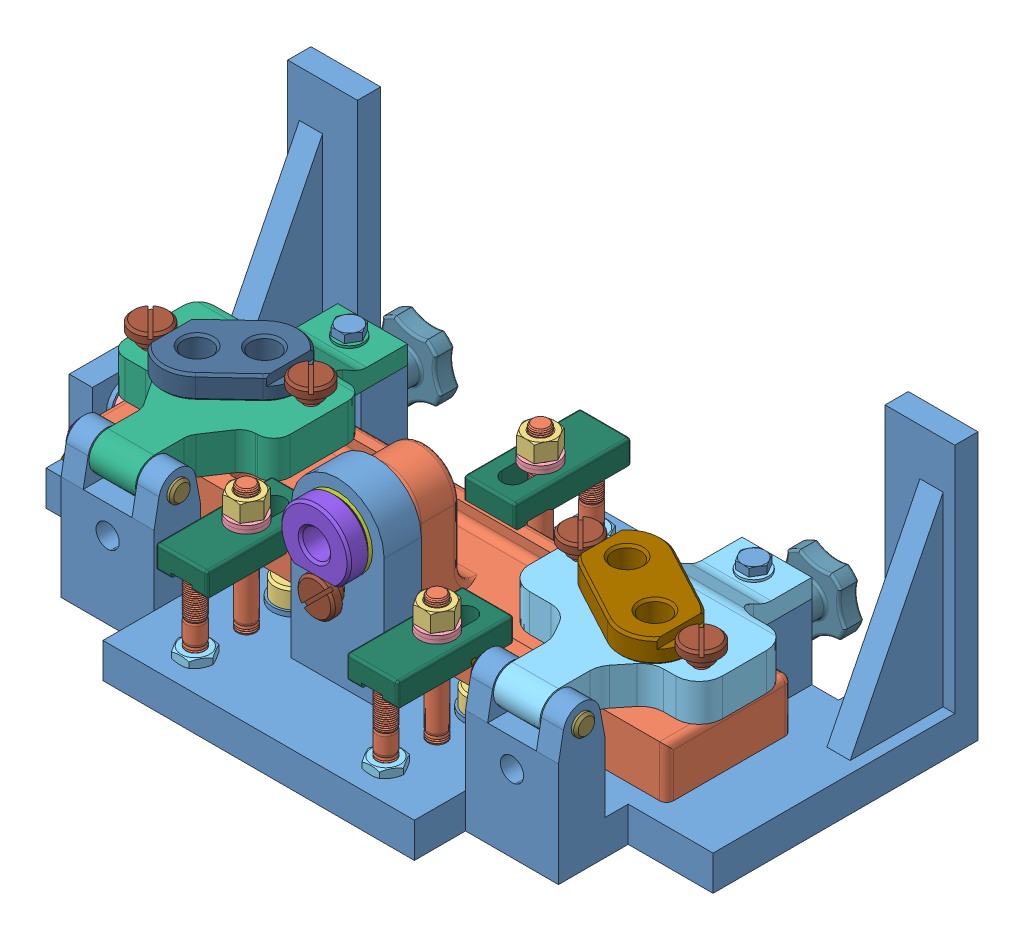
SolidWorks assembly 钻床夹具_4, configuration 默认. Lengths in mm.
Overall size (287 115 166).
59 component instances, 23 part files, 146 mates.
Components (placement in the parent):
- 钻床夹具（新1）-1: 钻床夹具（新1） [默认] at (194.1772 106.0566 199.8684) size (287 115 166)
- 前横架-1: 前横架 [默认] at (70.6772 129.0566 147.8684) x (1 0 0) z (0 1 0) size (247 54 64)
- A型支承钉-1: A型支承钉 [默认] at (194.1772 131.0566 96.8684) size (16 20 16)
- B型支承钉-1: B型支承钉 [默认] at (281.1772 139.0566 147.8684) x (1 0 0) z (0 1 0) size (16 20 16)
- A型支承钉-2: A型支承钉 [默认] at (235.1772 131.0566 143.8684) size (16 20 16)
- A型支承钉-3: A型支承钉 [默认] at (153.1772 131.0566 143.8684) size (16 20 16)
- B型支承钉-2: B型支承钉 [默认] at (107.1772 139.0566 147.8684) x (1 0 0) z (0 1 0) size (16 20 16)
- B型支承钉-3: B型支承钉 [默认] at (70.6772 139.0566 122.8684) x (0 0 1) z (0 1 0) size (16 20 16)
- 钻模板大-1: 钻模板大 [默认] at (292.6772 153.0566 127.8684) size (83 16 112)
- 钻模板小-1: 钻模板小 [默认] at (95.6772 153.0566 127.8684) size (71 16 112)
- 衬套-1: 衬套 [默认] at (194.1772 178.0566 149.8684) x (1 0 0) z (0 -1 0) size (30 16 30)
- 可换钻套-1: 可换钻套 [默认] at (194.1772 178.0566 149.8684) x (0 -1 0) z (-1 0 0) size (30 26 30)
- 特殊钻套1-1: 特殊钻套1 [默认] at (292.6772 153.0566 127.8684) x (1 0 0) z (0 1 0) size (56 44 26)
- 特殊钻套2-1: 特殊钻套2 [默认] at (110.6772 153.0566 113.8684) x (-1 0 0) z (0 1 0) size (45 44 26)
- 钻套螺钉M6×4-2: 钻套螺钉M6×4 [默认] at (194.1772 158.0566 157.8684) x (-0.707107 -0.707107 0) z (-0.707107 0.707107 0) size (16 18 16)
- 钻套螺钉M6×4-1: 钻套螺钉M6×4 [默认] at (130.6772 161.0566 113.8684) x (0.707107 0 0.707107) z (-0.707107 0 0.707107) size (16 18 16)
- 钻套螺钉M6×4-3: 钻套螺钉M6×4 [默认] at (75.6772 161.0566 127.8684) x (-0.707107 0 -0.707107) z (0.707107 0 -0.707107) size (16 18 16)
- 钻套螺钉M6×4-4: 钻套螺钉M6×4 [默认] at (246.6772 161.0566 113.8684) x (0.707107 0 0.707107) z (-0.707107 0 0.707107) size (16 18 16)
- 钻套螺钉M6×4-5: 钻套螺钉M6×4 [默认] at (312.6772 161.0566 127.8684) x (0.707107 0 0.707107) z (-0.707107 0 0.707107) size (16 18 16)
- 铰链轴-1: 铰链轴 [默认] at (256.1772 161.0566 167.8684) x (0 -0.707107 0.707107) z (-1 0 0) size (9 9 47)
- 铰链轴-2: 铰链轴 [默认] at (82.1772 161.0566 167.8684) x (0 0.707107 0.707107) z (-1 0 0) size (9 9 47)
- AM6×50压紧螺钉-1: AM6×50压紧螺钉 [默认] at (281.1772 139.0566 43.8684) x (-0.707107 -0.707107 0) z (0 0 -1) size (6.06 6.06 49.99)
- AM6×50压紧螺钉-2: AM6×50压紧螺钉 [默认] at (107.1772 139.0566 43.8684) x (-0.707107 -0.707107 0) z (0 0 -1) size (6.06 6.06 49.99)
- BM6星形把手-1: BM6星形把手 [默认] at (281.1772 139.0566 41.8684) x (-0.707107 0.707107 0) z (0 0 -1) size (31.86 30.53 18.06)
- BM6星形把手-2: BM6星形把手 [默认] at (107.1772 139.0566 41.8684) x (-0.707107 0.707107 0) z (0 0 -1) size (31.86 30.53 18.06)
- A8×50移动压板-2: A8×50移动压板 [默认] at (224.1772 151.0566 142.1184) x (0 0 1) z (-1 0 0) size (50 10 22)
- A8×50移动压板-3: A8×50移动压板 [默认] at (205.1772 151.0566 100.6184) x (0 0 -1) z (1 0 0) size (50 10 22)
- A8×50移动压板-1: A8×50移动压板 [默认] at (142.1772 151.0566 142.1184) x (0 0 1) z (-1 0 0) size (50 10 22)
- 辅助支撑螺柱_小-1: 辅助支撑螺柱_小 [默认] at (103.1772 101.7128 120.8684) size (8 20 8)
- 辅助支撑螺柱_小-2: 辅助支撑螺柱_小 [默认] at (279.6772 101.7128 120.8684) size (8 20 8)
- plain washers-n series-grade a gb-1: plain washers-n series-grade a gb [GB_FASTENER_WASHER_PWNA 6] at (85.3188 161.0566 167.8684) x (0 0 1) z (-1 0 0) size (12 12 1.6)
- plain washers-n series-grade a gb-2: plain washers-n series-grade a gb [GB_FASTENER_WASHER_PWNA 6] at (259.4007 161.0566 167.8684) x (0 0 1) z (-1 0 0) size (12 12 1.6)
- split pins-1: split pins [GB_CONNECTING_PIECE_PIN_AP 1.6X10] at (84.6772 165.4406 163.4843) x (0 -0.707107 0.707107) z (1 0 0) size (15.7 2.8 1.4)
- split pins-2: split pins [GB_CONNECTING_PIECE_PIN_AP 1.6X10] at (258.6772 165.4406 172.2525) x (0 -0.707107 -0.707107) z (1 0 0) size (15.7 2.8 1.4)
- hex head bolts-full thread grade c gb-7: hex head bolts-full thread grade c gb [GB_FASTENER_BOLT_HHBFTC M6X16-N] at (281.1772 166.0566 73.8686) x (0 -1 0) z (-0.866025 0 0.5) size (20 11.55 10)
- hex head bolts-full thread grade c gb-6: hex head bolts-full thread grade c gb [GB_FASTENER_BOLT_HHBFTC M6X16-N] at (107.1772 166.0566 73.8684) x (0 -1 0) z (0 0 -1) size (20 11.55 10)
- double end studs bm=2d gb-1: double end studs bm=2d gb [GB_FASTENER_BOLT_DESB20 A M8X25-S] at (235.1772 112.0566 186.1184) x (0 1 0) z (0 0 1) size (41 8 8)
- double end studs bm=2d gb-2: double end studs bm=2d gb [GB_FASTENER_BOLT_DESB20 A M8X50-S] at (235.1772 109.0566 164.1184) x (0 1 0) z (0 0 1) size (66 8 8)
- hex nut-fine pitch-style washer-grade ab gb-1: hex nut-fine pitch-style washer-grade ab gb [GB_HEXAGON_TYPE10_1 M8X1-S] at (235.1772 164.8566 164.1184) x (-1 0 0) z (0 -1 0) size (15.01 13 8.1)
- double end studs bm=2d gb-3: double end studs bm=2d gb [GB_FASTENER_BOLT_DESB20 A M8X50-S] at (153.1772 109.0566 164.1184) x (0 1 0) z (0.210743 0 0.977541) size (66 8 8)
- double end studs bm=2d gb-4: double end studs bm=2d gb [GB_FASTENER_BOLT_DESB20 A M8X50-S] at (194.1772 109.0566 78.6184) x (0 1 0) z (-0.024503 0 0.9997) size (66 8 8)
- hex nut-fine pitch-style washer-grade ab gb-2: hex nut-fine pitch-style washer-grade ab gb [GB_HEXAGON_TYPE10_1 M8X1-S] at (153.1772 164.8566 164.1184) x (-1 0 0) z (0 -1 0) size (15.01 13 8.1)
- double end studs bm=2d gb-5: double end studs bm=2d gb [GB_FASTENER_BOLT_DESB20 A M8X25-S] at (153.1772 112.0566 186.1184) x (0 1 0) z (0 0 1) size (41 8 8)
- double end studs bm=2d gb-6: double end studs bm=2d gb [GB_FASTENER_BOLT_DESB20 A M8X25-S] at (194.1772 112.0566 56.6184) x (0 1 0) z (0 0 1) size (41 8 8)
- plain washers-s series-grade a gb-1: plain washers-s series-grade a gb [GB_FASTENER_WASHER_PWSA 8] at (235.1772 162.6566 164.1184) x (-0.768939 0 -0.639322) z (0 1 0) size (15 15 1.6)
- plain washers-s series-grade a gb-2: plain washers-s series-grade a gb [GB_FASTENER_WASHER_PWSA 8] at (235.1772 162.6566 164.1184) x (-0.41646 0 0.909154) z (0 -1 0) size (15 15 1.6)
- plain washers-n series-grade a gb-4: plain washers-n series-grade a gb [GB_FASTENER_WASHER_PWNA 8] at (235.1772 151.0566 164.1184) x (1 0 0) z (0 1 0) size (16 16 1.6)
- hex nut-fine pitch-style washer-grade ab gb-3: hex nut-fine pitch-style washer-grade ab gb [GB_HEXAGON_TYPE10_1 M8X1-S] at (194.1772 164.8566 78.6184) x (-1 0 0) z (0 -1 0) size (15.01 13 8.1)
- plain washers-s series-grade a gb-3: plain washers-s series-grade a gb [GB_FASTENER_WASHER_PWSA 8] at (153.1772 161.0566 164.1184) x (1 0 0) z (0 -1 0) size (15 15 1.6)
- plain washers-s series-grade a gb-4: plain washers-s series-grade a gb [GB_FASTENER_WASHER_PWSA 8] at (153.1772 162.6566 164.1184) x (1 0 0) z (0 -1 0) size (15 15 1.6)
- plain washers-s series-grade a gb-5: plain washers-s series-grade a gb [GB_FASTENER_WASHER_PWSA 8] at (194.1772 164.2566 78.6184) x (1 0 0) z (0 1 0) size (15 15 1.6)
- plain washers-s series-grade a gb-6: plain washers-s series-grade a gb [GB_FASTENER_WASHER_PWSA 8] at (194.1772 162.6566 78.6184) x (1 0 0) z (0 1 0) size (15 15 1.6)
- plain washers-n series-grade a gb-3: plain washers-n series-grade a gb [GB_FASTENER_WASHER_PWNA 8] at (153.1772 151.0566 164.1184) x (1 0 0) z (0 1 0) size (16 16 1.6)
- plain washers-n series-grade a gb-5: plain washers-n series-grade a gb [GB_FASTENER_WASHER_PWNA 8] at (194.1772 151.0566 78.6184) x (1 0 0) z (0 1 0) size (16 16 1.6)
- hex thin nuts-grades ab-chamfered gb-1: hex thin nuts-grades ab-chamfered gb [GB_FASTENER_NUT_STNAB M8-N] at (153.1772 125.0566 186.1184) x (1 0 0) z (0 1 0) size (15.01 13 4)
- hex thin nuts-grades ab-chamfered gb-2: hex thin nuts-grades ab-chamfered gb [GB_FASTENER_NUT_STNAB M8-N] at (235.1772 125.0566 186.1184) x (1 0 0) z (0 1 0) size (15.01 13 4)
- hex thin nuts-grades ab-chamfered gb-3: hex thin nuts-grades ab-chamfered gb [GB_FASTENER_NUT_STNAB M8-N] at (194.1772 125.0566 56.6184) x (1 0 0) z (0 1 0) size (15.01 13 4)
- hex thin nuts-grades ab-chamfered gb-4: hex thin nuts-grades ab-chamfered gb [GB_FASTENER_NUT_STNAB M8-N] at (103.1772 125.0566 120.8684) x (1 0 0) z (0 1 0) size (15.01 13 4)
- hex thin nuts-grades ab-chamfered gb-5: hex thin nuts-grades ab-chamfered gb [GB_FASTENER_NUT_STNAB M8-N] at (279.6772 125.0566 120.8684) x (1 0 0) z (0 1 0) size (15.01 13 4)
Mates (geometry in assembly coordinates):
- 同心1: concentric: cylinder of assembly; cylinder of assembly; cylinder of 钻床夹具（新1）-1 through (235.1772 108.0566 143.8684) axis (0 1 0) radius 5; cylinder of A型支承钉-2 through (235.1772 111.0566 143.8684) axis (0 -1 0) radius 5
- 重合1: coincident: plane of assembly; plane of assembly; plane of 钻床夹具（新1）-1 through (235.1772 123.0566 143.8684) normal (0 1 0); plane of A型支承钉-2 through (243.1772 123.0566 143.8684) normal (0 -1 0)
- 同心2: concentric: cylinder of assembly; cylinder of assembly; cylinder of 钻床夹具（新1）-1 through (153.1772 108.0566 143.8684) axis (0 1 0) radius 5; cylinder of A型支承钉-3 through (153.1772 111.0566 143.8684) axis (0 -1 0) radius 5
- 重合2: coincident: plane of assembly; plane of assembly; plane of 钻床夹具（新1）-1 through (153.1772 123.0566 143.8684) normal (0 1 0); plane of A型支承钉-3 through (161.1772 123.0566 143.8684) normal (0 -1 0)
- 同心3: concentric: cylinder of assembly; cylinder of assembly; cylinder of 钻床夹具（新1）-1 through (194.1772 108.0566 96.8684) axis (0 1 0) radius 5; cylinder of A型支承钉-1 through (194.1772 111.0566 96.8684) axis (0 -1 0) radius 5
- 重合3: coincident: plane of assembly; plane of assembly; plane of 钻床夹具（新1）-1 through (194.1772 123.0566 96.8684) normal (0 1 0); plane of A型支承钉-1 through (202.1772 123.0566 96.8684) normal (0 -1 0)
- 同心4: concentric: cylinder of assembly; cylinder of assembly; cylinder of 钻床夹具（新1）-1 through (107.1772 139.0566 199.8694) axis (0 0 -1) radius 5; cylinder of B型支承钉-2 through (107.1772 139.0566 167.8684) axis (0 0 1) radius 5
- 重合4: coincident: plane of assembly; plane of assembly; plane of 钻床夹具（新1）-1 through (107.1772 139.0566 155.8684) normal (0 0 -1); plane of B型支承钉-2 through (115.1772 139.0566 155.8684) normal (0 0 1)
- 同心5: concentric: cylinder of assembly; cylinder of assembly; cylinder of 钻床夹具（新1）-1 through (281.1772 139.0566 199.8694) axis (0 0 -1) radius 5; cylinder of B型支承钉-1 through (281.1772 139.0566 167.8684) axis (0 0 1) radius 5
- 重合5: coincident: plane of assembly; plane of assembly; plane of 钻床夹具（新1）-1 through (281.1772 139.0566 155.8684) normal (0 0 -1); plane of B型支承钉-1 through (289.1772 139.0566 155.8684) normal (0 0 1)
- 同心6: concentric: cylinder of assembly; cylinder of assembly; cylinder of 钻床夹具（新1）-1 through (50.6762 139.0566 122.8684) axis (1 0 0) radius 5; cylinder of B型支承钉-3 through (50.6772 139.0566 122.8684) axis (-1 0 0) radius 5
- 重合6: coincident: plane of assembly; plane of assembly; plane of 钻床夹具（新1）-1 through (62.6772 139.0566 122.8684) normal (1 0 0); plane of B型支承钉-3 through (62.6772 139.0566 130.8684) normal (-1 0 0)
- 相切1: tangent: plane of assembly; sphere of assembly; plane of 前横架-1 through (70.6772 151.0566 147.8684) normal (-1 0 0); sphere of B型支承钉-3
- 相切2: tangent: sphere of assembly; plane of assembly; sphere of B型支承钉-1; plane of 前横架-1 through (70.6772 151.0566 147.8684) normal (0 0 1)
- 重合7: coincident: plane of assembly; plane of assembly; plane of A型支承钉-1 through (194.1772 131.0566 96.8684) normal (0 1 0); plane of 前横架-1 through (70.6772 131.0566 147.8684) normal (0 -1 0)
- 相切4: tangent: plane of assembly; sphere of assembly; plane of 前横架-1 through (70.6772 151.0566 147.8684) normal (0 0 1); sphere of B型支承钉-2
- 同心7: concentric: cylinder of assembly; cylinder of assembly; cylinder of 钻床夹具（新1）-1 through (269.6625 161.0566 167.8684) axis (-1 0 0) radius 3; cylinder of 钻模板小-1 through (67.6762 161.0566 167.8684) axis (1 0 0) radius 3
- 距离1: distance = 0.5 mm: plane of assembly; plane of assembly; plane of 钻模板小-1 through (117.1772 169.0566 152.8684) normal (1 0 0); plane of 钻床夹具（新1）-1 through (117.6772 198.0576 157.8684) normal (-1 0 0)
- 重合9: coincident: plane of assembly; plane of assembly; plane of 钻床夹具（新1）-1 through (194.1772 153.0566 199.8684) normal (0 1 0); plane of 钻模板小-1 through (95.6772 153.0566 127.8684) normal (0 -1 0)
- 重合10: coincident: plane of assembly; plane of assembly; plane of 钻床夹具（新1）-1 through (194.1772 153.0566 199.8684) normal (0 1 0); plane of 钻模板大-1 through (292.6772 153.0566 127.8684) normal (0 -1 0)
- 同心8: concentric: cylinder of assembly; cylinder of assembly; cylinder of 钻床夹具（新1）-1 through (252.6919 161.0566 167.8684) axis (1 0 0) radius 3; cylinder of 钻模板大-1 through (271.1772 161.0566 167.8684) axis (1 0 0) radius 3
- 距离2: distance = 0.5 mm: plane of assembly; plane of assembly; plane of 钻床夹具（新1）-1 through (270.6772 198.0576 157.8684) normal (1 0 0); plane of 钻模板大-1 through (271.1772 169.0566 150.8684) normal (-1 0 0)
- 同心9: concentric: cylinder of assembly; cylinder of assembly; cylinder of 钻床夹具（新1）-1 through (194.1772 178.0566 43.8674) axis (0 0 1) radius 13; cylinder of 衬套-1 through (194.1772 178.0566 165.8684) axis (0 0 1) radius 13
- 重合12: coincident: plane of assembly; plane of assembly; plane of 钻床夹具（新1）-1 through (194.1772 178.0566 162.8684) normal (0 0 1); plane of 衬套-1 through (206.1772 178.0566 162.8684) normal (0 0 -1)
- 同心10: concentric: cylinder of assembly; cylinder of assembly; cylinder of 衬套-1 through (194.1772 178.0566 149.8684) axis (0 0 1) radius 9; cylinder of 可换钻套-1 through (194.1772 178.0566 175.8684) axis (0 0 1) radius 9
- 重合13: coincident: plane of assembly; plane of assembly; plane of 衬套-1 through (209.1772 178.0566 165.8684) normal (0 0 1); plane of 可换钻套-1 through (194.1772 178.0566 165.8684) normal (0 0 -1)
- 同心11: concentric: cylinder of assembly; cylinder of assembly; cylinder of 钻床夹具（新1）-1 through (194.1772 158.0566 153.8684) axis (0 0 1) radius 3; cylinder of 钻套螺钉M6×4-2 through (194.1772 158.0566 175.8684) axis (0 0 1) radius 3
- 重合14: coincident: plane of assembly; plane of assembly; plane of 可换钻套-1 through (194.1772 178.0566 171.8684) normal (0 0 1); plane of 钻套螺钉M6×4-2 through (190.8184 154.6978 171.8684) normal (0 0 -1)
- 同心12: concentric: cylinder of assembly; cylinder of assembly; cylinder of 钻模板大-1 through (266.6772 169.0566 113.8684) axis (0 -1 0) radius 9; cylinder of 特殊钻套1-1 through (266.6772 169.0566 113.8684) axis (0 -1 0) radius 9
- 同心13: concentric: cylinder of assembly; cylinder of assembly; cylinder of 钻模板大-1 through (292.6772 169.0566 127.8684) axis (0 -1 0) radius 9; cylinder of 特殊钻套1-1 through (292.6772 169.0566 127.8684) axis (0 -1 0) radius 9
- 重合15: coincident: plane of assembly; plane of assembly; plane of 钻模板大-1 through (292.6772 169.0566 127.8684) normal (0 1 0); plane of 特殊钻套1-1 through (292.6772 169.0566 127.8684) normal (0 -1 0)
- 同心14: concentric: cylinder of assembly; cylinder of assembly; cylinder of 钻模板小-1 through (110.6772 169.0566 113.8684) axis (0 -1 0) radius 9; cylinder of 特殊钻套2-1 through (110.6772 169.0566 113.8684) axis (0 -1 0) radius 9
- 同心15: concentric: cylinder of assembly; cylinder of assembly; cylinder of 钻模板小-1 through (95.6772 169.0566 127.8684) axis (0 -1 0) radius 9; cylinder of 特殊钻套2-1 through (95.6772 169.0566 127.8684) axis (0 -1 0) radius 9
- 重合16: coincident: plane of assembly; plane of assembly; plane of 钻模板小-1 through (95.6772 169.0566 127.8684) normal (0 1 0); plane of 特殊钻套2-1 through (110.6772 169.0566 113.8684) normal (0 -1 0)
- 重合17: coincident: plane of assembly; plane of assembly; plane of 特殊钻套2-1 through (95.6772 175.0566 127.8684) normal (0 1 0); plane of 钻套螺钉M6×4-3 through (72.3184 175.0566 124.5096) normal (0 -1 0)
- 同心17: concentric: cylinder of assembly; cylinder of assembly; cylinder of 钻模板小-1 through (75.6772 169.0566 127.8684) axis (0 -1 0) radius 3; cylinder of 钻套螺钉M6×4-3 through (75.6772 179.0566 127.8684) axis (0 1 0) radius 3
- 重合18: coincident: plane of assembly; plane of assembly; plane of 特殊钻套2-1 through (110.6772 175.0566 113.8684) normal (0 1 0); plane of 钻套螺钉M6×4-1 through (134.0359 175.0566 117.2272) normal (0 -1 0)
- 重合19: coincident: plane of assembly; plane of assembly; plane of 特殊钻套1-1 through (266.6772 175.0566 113.8684) normal (0 1 0); plane of 钻套螺钉M6×4-4 through (250.0359 175.0566 117.2272) normal (0 -1 0)
- 重合20: coincident: plane of assembly; plane of assembly; plane of 钻套螺钉M6×4-5 through (316.0359 175.0566 131.2272) normal (0 -1 0); plane of 特殊钻套1-1 through (292.6772 175.0566 127.8684) normal (0 1 0)
- 同心18: concentric: cylinder of assembly; cylinder of assembly; cylinder of 钻模板大-1 through (312.6772 169.0566 127.8684) axis (0 -1 0) radius 3; cylinder of 钻套螺钉M6×4-5 through (312.6772 179.0566 127.8684) axis (0 1 0) radius 3
- 同心19: concentric: cylinder of assembly; cylinder of assembly; cylinder of 钻模板大-1 through (246.6772 169.0566 113.8684) axis (0 -1 0) radius 3; cylinder of 钻套螺钉M6×4-4 through (246.6772 179.0566 113.8684) axis (0 1 0) radius 3
- 同心20: concentric: cylinder of assembly; cylinder of assembly; cylinder of 钻模板小-1 through (130.6772 169.0566 113.8684) axis (0 -1 0) radius 3; cylinder of 钻套螺钉M6×4-1 through (130.6772 179.0566 113.8684) axis (0 1 0) radius 3
- 相切6: tangent: plane of assembly; sphere of assembly; plane of 前横架-1 through (70.6772 151.0566 93.8684) normal (0 0 -1); sphere of AM6×50压紧螺钉-1
- 同心21: concentric: cylinder of assembly; cylinder of assembly; cylinder of 钻床夹具（新1）-1 through (281.1772 139.0566 83.8684) axis (0 0 -1) radius 3; cylinder of AM6×50压紧螺钉-1 through (281.1772 139.0566 43.8684) axis (0 0 -1) radius 2.25
- 同心22: concentric: cylinder of assembly; cylinder of assembly; cylinder of 钻床夹具（新1）-1 through (107.1772 139.0566 83.8684) axis (0 0 -1) radius 3; cylinder of AM6×50压紧螺钉-2 through (107.1772 139.0566 43.8684) axis (0 0 -1) radius 2.25
- 相切7: tangent: plane of assembly; sphere of assembly; plane of 前横架-1 through (70.6772 151.0566 93.8684) normal (0 0 -1); sphere of AM6×50压紧螺钉-2
- 同心23: concentric: cylinder of assembly; cylinder of assembly; cylinder of AM6×50压紧螺钉-2 through (107.1772 139.0566 43.8684) axis (0 0 -1) radius 2.25; cylinder of BM6星形把手-2 through (107.1772 139.0566 41.8684) axis (0 0 -1) radius 7
- 同心24: concentric: cylinder of assembly; cylinder of assembly; cylinder of AM6×50压紧螺钉-2 through (109.2985 141.1779 54.8684) axis (-0.707107 -0.707107 0) radius 1; cylinder of BM6星形把手-2 through (96.9396 128.819 54.8684) axis (0.707107 0.707107 0) radius 1
- 同心25: concentric: cylinder of assembly; cylinder of assembly; cylinder of AM6×50压紧螺钉-1 through (283.2985 141.1779 54.8684) axis (-0.707107 -0.707107 0) radius 1; cylinder of BM6星形把手-1 through (270.9396 128.819 54.8684) axis (0.707107 0.707107 0) radius 1
- 同心26: concentric: cylinder of assembly; cylinder of assembly; cylinder of AM6×50压紧螺钉-1 through (281.1772 139.0566 43.8684) axis (0 0 -1) radius 2.25; cylinder of BM6星形把手-1 through (281.1772 139.0566 41.8684) axis (0 0 -1) radius 7
- 同心27: concentric: cylinder of assembly; cylinder of assembly; cylinder of 钻床夹具（新1）-1 through (252.6919 161.0566 167.8684) axis (1 0 0) radius 3; cylinder of 铰链轴-1 through (303.1772 161.0566 167.8684) axis (1 0 0) radius 3
- 重合21: coincident: plane of assembly; plane of assembly; plane of 钻床夹具（新1）-1 through (301.1772 121.0566 147.8684) normal (1 0 0); plane of 铰链轴-1 through (301.1772 162.4708 166.4542) normal (-1 0 0)
- 同心28: concentric: cylinder of assembly; cylinder of assembly; cylinder of 钻床夹具（新1）-1 through (269.6625 161.0566 167.8684) axis (-1 0 0) radius 3; cylinder of 铰链轴-2 through (129.1772 161.0566 167.8684) axis (1 0 0) radius 3
- 重合22: coincident: plane of assembly; plane of assembly; plane of 钻床夹具（新1）-1 through (127.1772 151.0566 177.8684) normal (1 0 0); plane of 铰链轴-2 through (127.1772 159.6423 166.4542) normal (-1 0 0)
- 同心29: concentric: cylinder of assembly; cylinder of assembly; cylinder of 铰链轴-2 through (84.6772 157.8746 171.0504) axis (0 0.707107 -0.707107) radius 0.7; cylinder of split pins-1 through (84.6772 163.1779 165.7471) axis (0 -0.707107 0.707107) radius 0.7
- 同心30: concentric: cylinder of assembly; cylinder of assembly; cylinder of 铰链轴-2 through (129.1772 161.0566 167.8684) axis (1 0 0) radius 3; cylinder of plain washers-n series-grade a gb-1 through (86.9188 161.0566 167.8684) axis (-1 0 0) radius 3.2
- 同心31: concentric: cylinder of assembly; cylinder of assembly; cylinder of 铰链轴-1 through (258.6772 157.8746 164.6864) axis (0 0.707107 0.707107) radius 0.7; cylinder of split pins-2 through (258.6772 163.1779 169.9897) axis (0 -0.707107 -0.707107) radius 0.7
- 同心32: concentric: cylinder of assembly; cylinder of assembly; cylinder of 铰链轴-1 through (303.1772 161.0566 167.8684) axis (1 0 0) radius 3; cylinder of plain washers-n series-grade a gb-2 through (261.0007 161.0566 167.8684) axis (-1 0 0) radius 3.2
- 相切8: tangent: curve of ?; circle of split pins-2
- 相切9: tangent: edge_curve of ?; circle of split pins-1
- 垂直1: perpendicular: plane of assembly; plane of assembly; plane of plain washers-n series-grade a gb-1 through (85.3188 161.0566 167.8684) normal (-1 0 0); plane of split pins-1 through (83.9772 163.1779 165.7471) normal (0 -0.707107 -0.707107); plane of assembly; plane of assembly; plane of plain washers-n series-grade a gb-2; plane of split pins-2
- 垂直2: perpendicular: plane of plain washers-n series-grade a gb-2 through (259.4007 161.0566 167.8684) normal (-1 0 0); plane of split pins-2 through (257.9772 163.1779 169.9897) normal (0 0.707107 -0.707107)
- 角度1: planar angle = 2.356194 rad: plane of assembly; plane of assembly; plane of split pins-1 through (83.9772 163.1779 165.7471) normal (0 -0.707107 -0.707107); plane of 钻床夹具（新1）-1 through (87.1772 121.0566 177.8684) normal (0 0 1)
- 角度2: planar angle = 0.785398 rad: plane of assembly; plane of assembly; plane of 钻床夹具（新1）-1 through (301.1772 121.0566 177.8684) normal (0 0 1); plane of split pins-2 through (257.9772 163.1779 169.9897) normal (0 0.707107 -0.707107)
- 重合32: coincident: circle of assembly; cylinder of assembly; circle of 钻模板大-1; cylinder of hex head bolts-full thread grade c gb-7 through (281.1772 146.0566 73.8686) axis (0 1 0) radius 3
- 重合33: coincident: plane of assembly; plane of assembly; plane of 钻模板大-1 through (281.1772 162.0566 73.8686) normal (0 1 0); plane of hex head bolts-full thread grade c gb-7 through (281.1772 162.0566 63.8686) normal (0 -1 0)
- 同心38: concentric: cylinder of assembly; cylinder of assembly; cylinder of 钻模板小-1 through (107.1772 153.0566 73.8684) axis (0 1 0) radius 3; cylinder of hex head bolts-full thread grade c gb-6 through (107.1772 146.0566 73.8684) axis (0 1 0) radius 3
- 重合34: coincident: plane of assembly; plane of assembly; plane of 钻模板小-1 through (107.1772 162.0566 73.8684) normal (0 1 0); plane of hex head bolts-full thread grade c gb-6 through (115.8374 162.0566 78.8684) normal (0 -1 0)
- 同心39: concentric: cylinder of assembly; cylinder of assembly; cylinder of 钻床夹具（新1）-1 through (153.1772 106.0566 164.1184) axis (0 1 0) radius 4; cylinder of A8×50移动压板-1 through (153.1772 161.0566 164.1184) axis (0 -1 0) radius 4.5
- 重合35: coincident: plane of assembly; plane of assembly; plane of 前横架-1 through (70.6772 151.0566 147.8684) normal (0 1 0); plane of A8×50移动压板-2 through (224.1772 151.0566 142.1184) normal (0 -1 0)
- 同心41: concentric: cylinder of assembly; cylinder of assembly; cylinder of 钻床夹具（新1）-1 through (235.1772 106.0566 164.1184) axis (0 1 0) radius 4; cylinder of A8×50移动压板-2 through (235.1772 161.0566 164.1184) axis (0 -1 0) radius 4.5
- 重合36: coincident: plane of assembly; plane of assembly; plane of 前横架-1 through (70.6772 151.0566 147.8684) normal (0 1 0); plane of A8×50移动压板-1 through (142.1772 151.0566 142.1184) normal (0 -1 0)
- 重合37: coincident: plane of assembly; plane of assembly; plane of 前横架-1 through (70.6772 151.0566 147.8684) normal (0 1 0); plane of A8×50移动压板-3 through (205.1772 151.0566 100.6184) normal (0 -1 0)
- 同心43: concentric: cylinder of 钻床夹具（新1）-1 through (194.1772 106.0566 78.6184) axis (0 1 0) radius 4; cylinder of A8×50移动压板-3 through (194.1772 161.0566 78.6184) axis (0 -1 0) radius 4.5
- 平行1: parallel: plane of 前横架-1 through (70.6772 151.0566 93.8684) normal (0 0 -1); plane of A8×50移动压板-3 through (205.1772 161.0566 50.6184) normal (0 0 -1)
- 同心44: concentric: cylinder of assembly; cylinder of assembly; cylinder of 钻床夹具（新1）-1 through (235.1772 106.0566 164.1184) axis (0 1 0) radius 4; cylinder of double end studs bm=2d gb-2 through (235.1772 107.7457 164.1184) axis (0 -1 0) radius 4
- 同心45: concentric: cylinder of assembly; cylinder of assembly; cylinder of 钻床夹具（新1）-1 through (235.1772 106.0566 186.1184) axis (0 1 0) radius 4; cylinder of double end studs bm=2d gb-1 through (235.1772 110.7457 186.1184) axis (0 -1 0) radius 4
- 重合38: coincident: plane of A8×50移动压板-2 through (235.1772 153.0566 152.1184) normal (0 -1 0); plane of double end studs bm=2d gb-1 through (231.1772 153.0566 186.1184) normal (0 1 0)
- 同心46: concentric: cylinder of double end studs bm=2d gb-2 through (235.1772 107.7457 164.1184) axis (0 -1 0) radius 4; cylinder of hex nut-fine pitch-style washer-grade ab gb-1 through (235.1772 172.3566 164.1184) axis (0 -1 0) radius 3.4585
- 同心47: concentric: cylinder of assembly; cylinder of assembly; cylinder of 钻床夹具（新1）-1 through (153.1772 106.0566 164.1184) axis (0 1 0) radius 4; cylinder of double end studs bm=2d gb-3 through (153.1772 107.7457 164.1184) axis (0 -1 0) radius 4
- 同心48: concentric: cylinder of hex nut-fine pitch-style washer-grade ab gb-2 through (153.1772 172.3566 164.1184) axis (0 -1 0) radius 3.4585; cylinder of double end studs bm=2d gb-3 through (153.1772 107.7457 164.1184) axis (0 -1 0) radius 4
- 同心49: concentric: cylinder of assembly; cylinder of assembly; cylinder of 钻床夹具（新1）-1 through (194.1772 106.0566 78.6184) axis (0 1 0) radius 4; cylinder of double end studs bm=2d gb-4 through (194.1772 107.7457 78.6184) axis (0 -1 0) radius 4
- 同心50: concentric: cylinder of double end studs bm=2d gb-4 through (194.1772 107.7457 78.6184) axis (0 -1 0) radius 4; cylinder of hex nut-fine pitch-style washer-grade ab gb-3 through (194.1772 172.3566 78.6184) axis (0 -1 0) radius 3.4585
- 同心51: concentric: cylinder of assembly; cylinder of assembly; cylinder of 钻床夹具（新1）-1 through (153.1772 106.0566 186.1184) axis (0 1 0) radius 4; cylinder of double end studs bm=2d gb-5 through (153.1772 110.7457 186.1184) axis (0 -1 0) radius 4
- 重合39: coincident: plane of A8×50移动压板-1 through (153.1772 153.0566 152.1184) normal (0 -1 0); plane of double end studs bm=2d gb-5 through (149.1772 153.0566 186.1184) normal (0 1 0)
- 同心52: concentric: cylinder of assembly; cylinder of assembly; cylinder of 钻床夹具（新1）-1 through (194.1772 106.0566 56.6184) axis (0 1 0) radius 4; cylinder of double end studs bm=2d gb-6 through (194.1772 110.7457 56.6184) axis (0 -1 0) radius 4
- 重合40: coincident: plane of A8×50移动压板-3 through (194.1772 153.0566 90.6184) normal (0 -1 0); plane of double end studs bm=2d gb-6 through (190.1772 153.0566 56.6184) normal (0 1 0)
- 距离3: distance = 12 mm: plane of 钻床夹具（新1）-1 through (194.1772 121.0566 199.8684) normal (0 1 0); plane of double end studs bm=2d gb-4 through (194.1772 109.0566 78.6184) normal (0 -1 0)
- 距离4: distance = 12 mm: plane of 钻床夹具（新1）-1 through (194.1772 121.0566 199.8684) normal (0 1 0); plane of double end studs bm=2d gb-2 through (235.1772 109.0566 164.1184) normal (0 -1 0)
- 距离5: distance = 12 mm: plane of 钻床夹具（新1）-1 through (194.1772 121.0566 199.8684) normal (0 1 0); plane of double end studs bm=2d gb-3 through (153.1772 109.0566 164.1184) normal (0 -1 0)
- 重合44: coincident: plane of assembly; plane of assembly; plane of A8×50移动压板-1 through (142.1772 161.0566 142.1184) normal (0 1 0); plane of plain washers-s series-grade a gb-3 through (153.1772 161.0566 164.1184) normal (0 -1 0)
- 同心53: concentric: cone of double end studs bm=2d gb-3 through (153.1772 166.7356 164.1184) axis (0 1 0); cylinder of plain washers-s series-grade a gb-3 through (153.1772 162.6566 164.1184) axis (0 -1 0) radius 4.2
- 重合45: coincident: plane of plain washers-s series-grade a gb-3 through (153.1772 162.6566 164.1184) normal (0 1 0); plane of plain washers-s series-grade a gb-4 through (153.1772 162.6566 164.1184) normal (0 -1 0)
- 同心54: concentric: cylinder of double end studs bm=2d gb-3 through (153.1772 169.171 164.1184) axis (0 1 0) radius 1047.1976; cylinder of plain washers-s series-grade a gb-4 through (153.1772 164.2566 164.1184) axis (0 -1 0) radius 4.2
- 同心55: concentric: circle of double end studs bm=2d gb-2; cylinder of plain washers-s series-grade a gb-1 through (235.1772 161.0566 164.1184) axis (0 1 0) radius 4.2
- 同心56: concentric: circle of double end studs bm=2d gb-2; cylinder of plain washers-s series-grade a gb-2 through (235.1772 164.2566 164.1184) axis (0 -1 0) radius 4.2
- 重合49: coincident: plane of A8×50移动压板-2 through (224.1772 161.0566 142.1184) normal (0 1 0); plane of plain washers-s series-grade a gb-1 through (235.1772 161.0566 164.1184) normal (0 -1 0)
- 重合50: coincident: plane of plain washers-s series-grade a gb-1 through (235.1772 162.6566 164.1184) normal (0 1 0); plane of plain washers-s series-grade a gb-2 through (235.1772 162.6566 164.1184) normal (0 -1 0)
- 重合51: coincident: plane of hex nut-fine pitch-style washer-grade ab gb-1 through (235.1772 164.2566 164.1184) normal (0 -1 0); plane of plain washers-s series-grade a gb-2 through (235.1772 164.2566 164.1184) normal (0 1 0)
- 同心57: concentric: circle of double end studs bm=2d gb-4; cylinder of plain washers-s series-grade a gb-5 through (194.1772 162.6566 78.6184) axis (0 1 0) radius 4.2
- 同心58: concentric: circle of double end studs bm=2d gb-4; cylinder of plain washers-s series-grade a gb-6 through (194.1772 161.0566 78.6184) axis (0 1 0) radius 4.2
- 重合52: coincident: plane of plain washers-s series-grade a gb-5 through (194.1772 162.6566 78.6184) normal (0 -1 0); plane of plain washers-s series-grade a gb-6 through (194.1772 162.6566 78.6184) normal (0 1 0)
- 重合53: coincident: plane of A8×50移动压板-3 through (205.1772 161.0566 100.6184) normal (0 1 0); plane of plain washers-s series-grade a gb-6 through (194.1772 161.0566 78.6184) normal (0 -1 0)
- 重合54: coincident: plane of hex nut-fine pitch-style washer-grade ab gb-3 through (194.1772 164.2566 78.6184) normal (0 -1 0); plane of plain washers-s series-grade a gb-5 through (194.1772 164.2566 78.6184) normal (0 1 0)
- 同心59: concentric: cylinder of double end studs bm=2d gb-3 through (153.1772 107.7457 164.1184) axis (0 -1 0) radius 4; cylinder of plain washers-n series-grade a gb-3 through (153.1772 149.4566 164.1184) axis (0 1 0) radius 4.2
- 同心60: concentric: cylinder of double end studs bm=2d gb-2 through (235.1772 107.7457 164.1184) axis (0 -1 0) radius 4; cylinder of plain washers-n series-grade a gb-4 through (235.1772 149.4566 164.1184) axis (0 1 0) radius 4.2
- 同心61: concentric: cylinder of double end studs bm=2d gb-4 through (194.1772 107.7457 78.6184) axis (0 -1 0) radius 4; cylinder of plain washers-n series-grade a gb-5 through (194.1772 149.4566 78.6184) axis (0 1 0) radius 4.2
- 重合55: coincident: plane of A8×50移动压板-1 through (142.1772 151.0566 142.1184) normal (0 -1 0); plane of plain washers-n series-grade a gb-3 through (153.1772 151.0566 164.1184) normal (0 1 0)
- 重合56: coincident: plane of A8×50移动压板-2 through (224.1772 151.0566 142.1184) normal (0 -1 0); plane of plain washers-n series-grade a gb-4 through (235.1772 151.0566 164.1184) normal (0 1 0)
- 重合57: coincident: plane of A8×50移动压板-3 through (205.1772 151.0566 100.6184) normal (0 -1 0); plane of plain washers-n series-grade a gb-5 through (194.1772 151.0566 78.6184) normal (0 1 0)
- 同心62: concentric: cylinder of hex thin nuts-grades ab-chamfered gb-1 through (153.1772 121.0566 186.1184) axis (0 1 0) radius 3.3235; cylinder of double end studs bm=2d gb-5 through (153.1772 110.7457 186.1184) axis (0 -1 0) radius 4
- 同心63: concentric: cylinder of hex thin nuts-grades ab-chamfered gb-2 through (235.1772 121.0566 186.1184) axis (0 1 0) radius 3.3235; cylinder of double end studs bm=2d gb-1 through (235.1772 110.7457 186.1184) axis (0 -1 0) radius 4
- 同心64: concentric: cylinder of double end studs bm=2d gb-6 through (194.1772 110.7457 56.6184) axis (0 -1 0) radius 4; cylinder of hex thin nuts-grades ab-chamfered gb-3 through (194.1772 121.0566 56.6184) axis (0 1 0) radius 3.3235
- 重合58: coincident: plane of 钻床夹具（新1）-1 through (194.1772 121.0566 199.8684) normal (0 1 0); plane of hex thin nuts-grades ab-chamfered gb-1 through (156.9299 121.0566 192.6184) normal (0 -1 0)
- 重合59: coincident: plane of 钻床夹具（新1）-1 through (194.1772 121.0566 199.8684) normal (0 1 0); plane of hex thin nuts-grades ab-chamfered gb-2 through (238.9299 121.0566 192.6184) normal (0 -1 0)
- 重合60: coincident: plane of 钻床夹具（新1）-1 through (194.1772 121.0566 199.8684) normal (0 1 0); plane of hex thin nuts-grades ab-chamfered gb-3 through (197.9299 121.0566 63.1184) normal (0 -1 0)
- 相切10: tangent: plane of assembly; sphere of assembly; plane of 前横架-1 through (70.6772 129.0566 147.8684) normal (0 -1 0); sphere of 辅助支撑螺柱_小-1
- 相切11: tangent: plane of assembly; sphere of assembly; plane of 前横架-1 through (70.6772 129.0566 147.8684) normal (0 -1 0); sphere of 辅助支撑螺柱_小-2
- 同心65: concentric: cylinder of 辅助支撑螺柱_小-1 through (103.1772 109.0566 120.8684) axis (0 -1 0) radius 4; circle of hex thin nuts-grades ab-chamfered gb-4
- 同心66: concentric: cylinder of 辅助支撑螺柱_小-2 through (279.6772 109.0566 120.8684) axis (0 -1 0) radius 4; cylinder of hex thin nuts-grades ab-chamfered gb-5 through (279.6772 121.0566 120.8684) axis (0 1 0) radius 3.3235
- 重合61: coincident: plane of 钻床夹具（新1）-1 through (194.1772 121.0566 199.8684) normal (0 1 0); plane of hex thin nuts-grades ab-chamfered gb-5 through (283.4299 121.0566 127.3684) normal (0 -1 0)
- 同心67: concentric: cylinder of 钻床夹具（新1）-1 through (279.6772 106.0566 120.8684) axis (0 1 0) radius 4; cylinder of 辅助支撑螺柱_小-2 through (279.6772 109.0566 120.8684) axis (0 -1 0) radius 4
- 重合62: coincident: plane of 钻床夹具（新1）-1 through (194.1772 121.0566 199.8684) normal (0 1 0); plane of hex thin nuts-grades ab-chamfered gb-4 through (106.9299 121.0566 127.3684) normal (0 -1 0)
- 同心68: concentric: cylinder of 钻床夹具（新1）-1 through (103.1772 106.0566 120.8684) axis (0 1 0) radius 4; cylinder of 辅助支撑螺柱_小-1 through (103.1772 109.0566 120.8684) axis (0 -1 0) radius 4
- 平行2: parallel: plane of A8×50移动压板-2 through (224.1772 161.0566 192.1184) normal (0 0 1); plane of hex nut-fine pitch-style washer-grade ab gb-1 through (238.9299 172.3566 170.6184) normal (0 0 1)
- 平行3: parallel: plane of A8×50移动压板-1 through (142.1772 161.0566 192.1184) normal (0 0 1); plane of hex nut-fine pitch-style washer-grade ab gb-2 through (156.9299 172.3566 170.6184) normal (0 0 1)
- 重合65: coincident: plane of hex nut-fine pitch-style washer-grade ab gb-2 through (153.1772 164.2566 164.1184) normal (0 -1 0); plane of plain washers-s series-grade a gb-4 through (153.1772 164.2566 164.1184) normal (0 1 0)
- 平行4: parallel: plane of 钻床夹具（新1）-1 through (87.1772 121.0566 177.8684) normal (0 0 1); plane of A8×50移动压板-1 through (142.1772 161.0566 192.1184) normal (0 0 1)
- 平行5: parallel: plane of 钻床夹具（新1）-1 through (301.1772 121.0566 177.8684) normal (0 0 1); plane of A8×50移动压板-2 through (224.1772 161.0566 192.1184) normal (0 0 1)
- 平行6: parallel: plane of 钻床夹具（新1）-1 through (182.1772 121.0566 43.8684) normal (0 0 -1); plane of A8×50移动压板-3 through (205.1772 161.0566 50.6184) normal (0 0 -1)
- 平行7: parallel: plane of A8×50移动压板-3 through (205.1772 161.0566 50.6184) normal (0 0 -1); plane of hex nut-fine pitch-style washer-grade ab gb-3 through (190.4244 172.3566 72.1184) normal (0 0 -1)
- 平行8: parallel: plane of 钻床夹具（新1）-1 through (127.1772 121.0566 199.8684) normal (0 0 1); plane of hex thin nuts-grades ab-chamfered gb-1 through (149.4244 121.0566 192.6184) normal (0 0 1)
- 平行9: parallel: plane of 钻床夹具（新1）-1 through (127.1772 121.0566 199.8684) normal (0 0 1); plane of hex thin nuts-grades ab-chamfered gb-2 through (231.4244 121.0566 192.6184) normal (0 0 1)
- 平行10: parallel: plane of 钻模板小-1 through (92.1772 169.0566 63.8684) normal (0 0 -1); plane of hex head bolts-full thread grade c gb-6 through (104.2904 162.0566 68.8684) normal (0 0 -1)
- 平行11: parallel: plane of 钻模板大-1 through (266.1772 169.0566 63.8686) normal (0 0 -1); plane of hex head bolts-full thread grade c gb-7 through (278.2904 162.0566 68.8686) normal (0 0 -1)
- 平行12: parallel: plane of 钻床夹具（新1）-1 through (182.1772 121.0566 43.8684) normal (0 0 -1); plane of hex thin nuts-grades ab-chamfered gb-3 through (197.9299 121.0566 50.1184) normal (0 0 -1)
- 平行13: parallel: plane of 钻床夹具（新1）-1 through (301.1772 121.0566 177.8684) normal (0 0 1); plane of hex thin nuts-grades ab-chamfered gb-5 through (275.9244 121.0566 127.3684) normal (0 0 1)
- 平行14: parallel: plane of 钻床夹具（新1）-1 through (87.1772 121.0566 177.8684) normal (0 0 1); plane of hex thin nuts-grades ab-chamfered gb-4 through (99.4244 121.0566 127.3684) normal (0 0 1)
- 角度8: planar angle = 0.785398 rad: plane of assembly; plane of assembly; plane of 钻床夹具（新1）-1 through (194.1772 121.0566 199.8684) normal (0 1 0); plane of AM6×50压紧螺钉-1 through (279.3576 136.6713 45.8684) normal (-0.707107 0.707107 0)
- 角度9: planar angle = 0.785398 rad: plane of assembly; plane of assembly; plane of 钻床夹具（新1）-1 through (194.1772 121.0566 199.8684) normal (0 1 0); plane of AM6×50压紧螺钉-2 through (105.3576 136.6713 45.8684) normal (-0.707107 0.707107 0); plane of assembly; plane of assembly; plane of 钻床夹具（新1）-1; plane of 可换钻套-1
- 平行21: parallel: plane of 钻床夹具（新1）-1 through (194.1772 121.0566 199.8684) normal (0 1 0); plane of 可换钻套-1 through (204.3752 167.0566 171.8684) normal (0 -1 0)
- 角度3: planar angle = 0.785398 rad: plane of assembly; plane of assembly; plane of 钻套螺钉M6×4-2 through (200.3394 163.1582 173.8684) normal (-0.707107 0.707107 0); plane of 钻床夹具（新1）-1 through (194.1772 121.0566 199.8684) normal (0 1 0)
- 角度4: planar angle = 2.356194 rad: plane of assembly; plane of assembly; plane of 钻床夹具（新1）-1 through (65.6772 163.5566 116.8684) normal (1 0 0); plane of 钻套螺钉M6×4-3 through (80.7788 177.0566 134.0307) normal (0.707107 0 -0.707107)
- 角度5: planar angle = 2.356194 rad: plane of assembly; plane of assembly; plane of 钻套螺钉M6×4-1 through (125.5756 177.0566 107.7061) normal (-0.707107 0 0.707107); plane of 钻床夹具（新1）-1 through (65.6772 163.5566 116.8684) normal (1 0 0)
- 角度6: planar angle = 2.356194 rad: plane of assembly; plane of assembly; plane of 钻套螺钉M6×4-4 through (241.5756 177.0566 107.7061) normal (-0.707107 0 0.707107); plane of 钻模板大-1 through (291.1772 169.0566 167.8684) normal (1 0 0)
- 角度7: planar angle = 0.785398 rad: plane of assembly; plane of assembly; plane of 钻套螺钉M6×4-5 through (307.5756 177.0566 121.7061) normal (-0.707107 0 0.707107); plane of 钻模板大-1 through (321.6772 169.0566 98.8686) normal (1 0 0)
